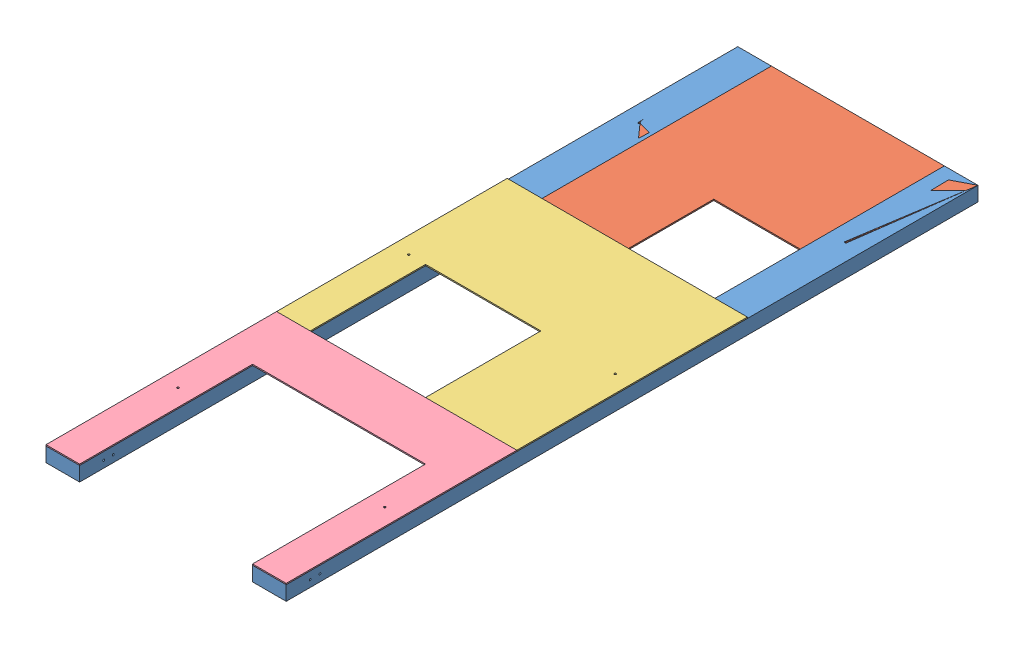
SolidWorks assembly Scoring, configuration Default. Lengths in mm.
Overall size (635 41.27 1828.8).
5 component instances, 4 part files, 8 mates.
Components (placement in the parent):
- Side-1: Side [Default] at (954.1971 1353.7776 989.1115) size (88.9 38.1 1828.8)
- Side-2: Side [Default] at (1500.2971 1353.7776 989.1115) size (88.9 38.1 1828.8)
- Top-1: Top [Default] at (1257.8239 1373.581 1166.4266) x (-1 0 0) z (0 -1 0) size (635 609.6 3.17)
- Middle-1: Middle [Default] at (1560.1502 1373.581 2035.1104) x (1 0 0) z (0 1 0) size (635 609.6 3.17)
- Bottom-1: Bottom [Default] at (1371.3637 1373.581 2734.8492) x (1 0 0) z (0 1 0) size (635 609.6 3.17)
Mates (geometry in assembly coordinates):
- Coincident10: coincident aligned: circle of Side-2; circle of Top-1
- Parallel1: parallel anti-aligned: line of Side-2 through (1564.9679 1373.581 2817.9115) axis (0 0 -1); line of Top-1 through (1564.9679 1370.406 989.1115) axis (0 0 1)
- Coincident12: coincident anti-aligned: circle of Side-1; circle of Middle-1
- Coincident13: coincident anti-aligned: circle of Side-2; circle of Middle-1
- Coincident14: coincident aligned: line of Side-2 through (1564.9679 1373.581 2817.9115) axis (0 0 -1); line of Middle-1 through (1564.9679 1373.581 2208.3115) axis (0 0 -1)
- Parallel2: parallel aligned: line of Side-1 through (929.9679 1373.581 2817.9115) axis (0 0 -1); line of Top-1 through (929.9679 1370.406 1598.7115) axis (0 0 -1)
- Coincident18: coincident: line of Side-1 through (929.9679 1373.581 2817.9115) axis (0 0 -1); line of Bottom-1 through (929.9679 1376.756 2208.3115) axis (0 0 1)
- Coincident20: coincident: circle of Side-1; circle of Bottom-1
